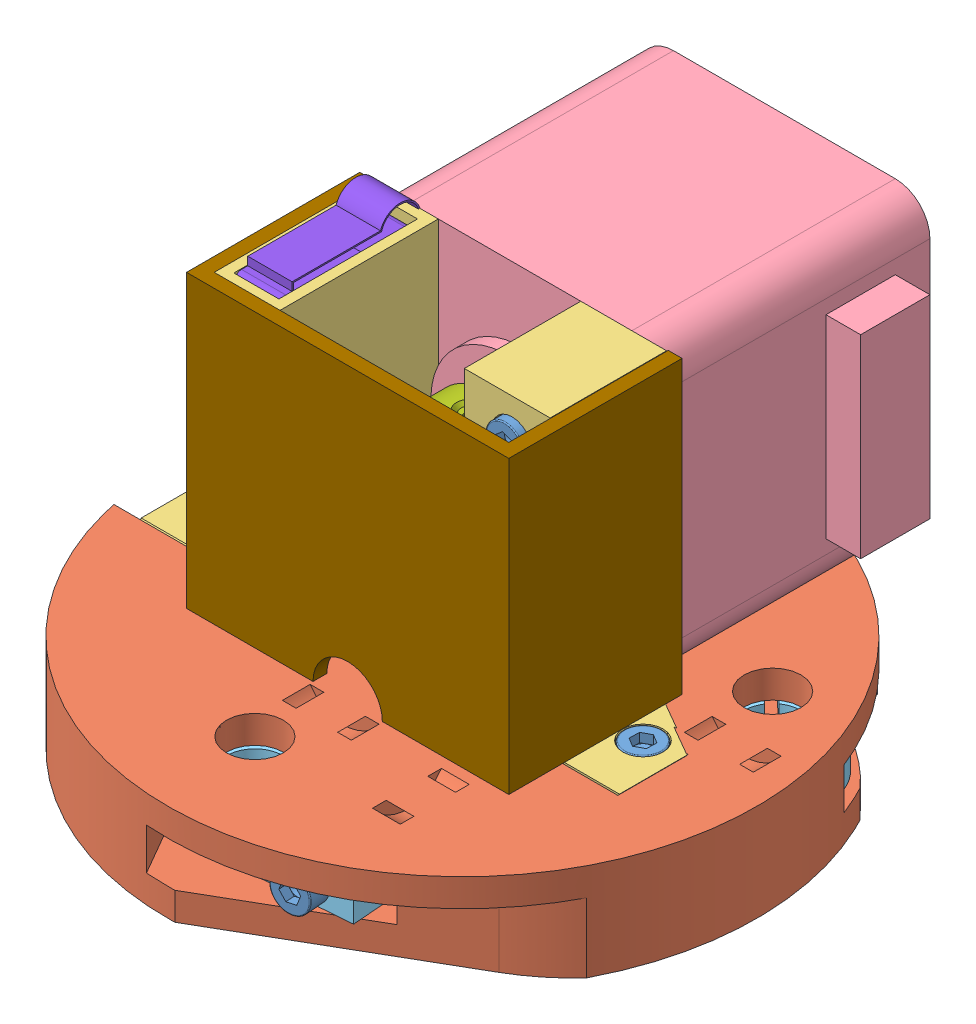
SolidWorks assembly PBaseAssembly, configuration Default. Lengths in mm.
Overall size (84.11 73.25 88.9).
22 component instances, 9 part files, 47 mates.
Components (placement in the parent):
- socket head cap screw_iso-3: socket head cap screw_iso [ISO 4762 M3 x 12 - 12N] at (26.05 4 0) x (0 -1 0) z (-0.999667 0 -0.02581) size (15 5.5 5.5)
- socket head cap screw_iso-7: socket head cap screw_iso [ISO 4762 M3 x 25 - 18N] at (-15.45 9.5 9.5) x (0 0 -1) z (0.981841 0.189707 0) size (28 5.5 5.5)
- socket head cap screw_iso-9: socket head cap screw_iso [ISO 4762 M3 x 16 - 16N] at (26.7408 -3.2 -33.0956) x (-0.692817 0 0.721114) z (-0.029148 0.999183 -0.028004) size (19 5.5 5.5)
- socket head cap screw_iso-10: socket head cap screw_iso [ISO 4762 M3 x 16 - 16N] at (-24.012 -3.2 -35.3724) x (0.554046 0 0.832486) z (-0.142507 -0.985239 0.094843) size (19 5.5 5.5)
- socket head cap screw_iso-13: socket head cap screw_iso [ISO 4762 M3 x 16 - 16N] at (12.3868 -3.2 37.2961) x (-0.079917 0 -0.996801) z (-0.160824 0.986899 0.012894) size (19 5.5 5.5)
- socket head cap screw_iso-11: socket head cap screw_iso [ISO 4762 M3 x 25 - 18N] at (15.55 40.5 9.5) x (0 0 -1) z (0.981841 0.189707 0) size (28 5.5 5.5)
- socket head cap screw_iso-12: socket head cap screw_iso [ISO 4762 M3 x 25 - 18N] at (15.55 9.5 8.5) x (0 0 -1) z (0.998806 -0.048858 0) size (28 5.5 5.5)
- socket head cap screw_iso-4: socket head cap screw_iso [ISO 4762 M3 x 12 - 12N] at (-25.95 4 0) x (0 -1 0) z (0.992841 0 -0.119448) size (15 5.5 5.5)
- PFestRound-1: PFestRound [Default] at origin size (84.11 28 85)
- PStepperHolder-1: PStepperHolder [Mit Kabelfuehrung] at (0.05 24.6603 -8.4) x (-1 0 0) z (0 0 -1) size (69 52 23)
- _Stepper_NEMA17-1: _Stepper_NEMA17 [Standard] at (0.05 25 -46.4) x (0 1 0) z (0 0 1) size (42 47 52)
- PRodFix-1: PRodFix [Default] at (29.25 -6 -15.5) x (-0.692817 0 0.721114) z (-0.721114 0 -0.692817) size (15.9 5.6 27.95)
- PRodFix-3: PRodFix [Default] at (-29.6 -0.4 -18.5) x (0.554046 0 0.832486) z (0.832486 0 -0.554046) size (15.9 5.6 27.95)
- PRodFix-6: PRodFix [Default] at (-2.4435 -6 27.5) x (-0.079917 0 -0.996801) z (0.996801 0 -0.079917) size (15.9 5.6 27.95)
- hex nut style 1 gradeab_iso-1: hex nut style 1 gradeab_iso [ISO - 4032 - M3 - D - N] at (10.8764 -3.2 18.4566) x (0 1 0) z (-0.079917 0 -0.996801) size (5.5 6.35 2.4)
- hex nut style 1 gradeab_iso-2: hex nut style 1 gradeab_iso [ISO - 4032 - M3 - D - N] at (13.6465 -3.2 -19.4666) x (0 -1 0) z (-0.692817 0 0.721114) size (5.5 6.35 2.4)
- hex nut style 1 gradeab_iso-3: hex nut style 1 gradeab_iso [ISO - 4032 - M3 - D - N] at (-13.5405 -3.2 -19.6384) x (0.720954 0.5 -0.479818) z (0.554046 0 0.832486) size (5.5 6.35 2.4)
- hex nut style 1 gradeab_iso-4: hex nut style 1 gradeab_iso [ISO - 4032 - M3 - D - N] at (-25.95 -10 0) x (0.866025 0 -0.5) z (0 -1 0) size (5.5 6.35 2.4)
- hex nut style 1 gradeab_iso-5: hex nut style 1 gradeab_iso [ISO - 4032 - M3 - D - N] at (26.05 -10 0) x (-0.866025 0 -0.5) z (0 -1 0) size (5.5 6.35 2.4)
- _Riemenscheibe_GT2_20T-1: _Riemenscheibe_GT2_20T [Конфигурация1] at (0.05 25 -3.8) x (0 0 1) z (-0.98079 0.195066 0) size (16 16 16)
- _Endschalter_15,6mm-2: _Endschalter_15,6mm [Default] at (-19.7782 35.8 3.2) x (0 0 -1) z (1 0 0) size (20.35 17.35 6.4)
- PStepperHolder_Cover-1: PStepperHolder_Cover [Default] at (-0.1282 25 14.4321) x (0 0 1) z (0 1 0) size (25 46.5 42)
Mates (geometry in assembly coordinates):
- Coincident1: coincident anti-aligned: plane of PFestRound-1 through (0 -6 0) normal (0 1 0); plane of PStepperHolder-1 through (-37.95 -6 -8.4) normal (0 -1 0)
- Concentric2: concentric aligned: cylinder of PFestRound-1 through (26.05 -10 0) axis (0 1 0) radius 1.7; cylinder of PStepperHolder-1 through (26.05 -6 0) axis (0 1 0) radius 1.7
- Concentric6: concentric aligned: cylinder of PStepperHolder-1 through (26.05 -6 0) axis (0 1 0) radius 1.7; cylinder of socket head cap screw_iso-3 through (26.05 35.75 0) axis (0 1 0) radius 1.5
- Coincident4: coincident anti-aligned: plane of PStepperHolder-1 through (26.05 1 0) normal (0 1 0); plane of socket head cap screw_iso-3 through (25.979 1 2.7491) normal (0 -1 0)
- Concentric9: concentric aligned: cylinder of PStepperHolder-1 through (-25.95 -6 0) axis (0 1 0) radius 1.7; cylinder of socket head cap screw_iso-4 through (-25.95 35.75 0) axis (0 1 0) radius 1.5
- Coincident7: coincident anti-aligned: plane of PStepperHolder-1 through (-25.95 1 0) normal (0 1 0); plane of socket head cap screw_iso-4 through (-26.2785 1 -2.7303) normal (0 -1 0)
- Concentric15: concentric aligned: cylinder of PFestRound-1 through (29.25 4 -15.5) axis (0 -1 0) radius 4.1; cylinder of PRodFix-1 through (29.25 -0.4 -15.5) axis (0 -1 0) radius 4.05
- Coincident13: coincident anti-aligned: plane of PFestRound-1 through (0 -6 0) normal (0 1 0); plane of PRodFix-1 through (29.25 -6 -15.5) normal (0 -1 0)
- Concentric17: concentric aligned: cylinder of PRodFix-1 through (13.6465 -3.2 -19.4666) axis (0.692817 0 -0.721114) radius 1.7; cylinder of socket head cap screw_iso-9 through (48.7377 -3.2 -55.991) axis (0.692817 0 -0.721114) radius 1.5
- Coincident14: coincident anti-aligned: plane of PRodFix-1 through (20.3356 -0.4 -35.0892) normal (0.692817 0 -0.721114); plane of socket head cap screw_iso-9 through (26.6437 -3.0888 -29.0286) normal (-0.692817 0 0.721114)
- Concentric18: concentric anti-aligned: cylinder of PFestRound-1 through (-29.6 4 -18.5) axis (0 -1 0) radius 4.1; cylinder of PRodFix-3 through (-29.6 -6 -18.5) axis (0 1 0) radius 4.05
- Coincident15: coincident anti-aligned: plane of PFestRound-1 through (0 -6 0) normal (0 1 0); plane of PRodFix-3 through (-29.6 -6 -18.5) normal (0 -1 0)
- Concentric19: concentric aligned: cylinder of PRodFix-3 through (-13.5405 -3.2 -19.6384) axis (-0.554046 0 -0.832486) radius 1.7; cylinder of socket head cap screw_iso-10 through (-41.603 -3.2 -61.8038) axis (-0.554046 0 -0.832486) radius 1.5
- Coincident16: coincident anti-aligned: plane of PRodFix-3 through (-17.3549 -6 -36.1992) normal (-0.554046 0 -0.832486); plane of socket head cap screw_iso-10 through (-24.6054 -2.7292 -31.3738) normal (0.554046 0 0.832486)
- Concentric21: concentric aligned: cylinder of socket head cap screw_iso-7 through (-15.45 9.5 41.25) axis (0 0 1) radius 1.5; cylinder of _Stepper_NEMA17-1 through (-15.45 9.5 -18.4) axis (0 0 1) radius 1.5
- Concentric22: concentric anti-aligned: cylinder of PStepperHolder-1 through (15.55 40.5 8.4) axis (0 0 -1) radius 1.7; cylinder of _Stepper_NEMA17-1 through (15.55 40.5 -18.4) axis (0 0 1) radius 1.5
- Coincident17: coincident anti-aligned: plane of PStepperHolder-1 through (0.05 24.6603 -8.4) normal (0 0 -1); plane of _Stepper_NEMA17-1 through (0.05 25 -8.4) normal (0 0 1)
- Concentric23: concentric anti-aligned: cylinder of PStepperHolder-1 through (-15.45 9.5 8.4) axis (0 0 -1) radius 1.7; cylinder of socket head cap screw_iso-7 through (-15.45 9.5 41.25) axis (0 0 1) radius 1.5
- Concentric24: concentric aligned: cylinder of _Stepper_NEMA17-1 through (15.55 40.5 -18.4) axis (0 0 1) radius 1.5; cylinder of socket head cap screw_iso-11 through (15.55 40.5 41.25) axis (0 0 1) radius 1.5
- Concentric25: concentric anti-aligned: cylinder of PStepperHolder-1 through (15.55 9.5 8.4) axis (0 0 -1) radius 1.7; cylinder of socket head cap screw_iso-12 through (15.55 9.5 40.25) axis (0 0 1) radius 1.5
- Concentric26: concentric aligned: cylinder of PFestRound-1 through (-2.4435 4 27.5) axis (0 -1 0) radius 4.1; cylinder of PRodFix-6 through (-2.4435 -0.4 27.5) axis (0 -1 0) radius 4.05
- Coincident21: coincident anti-aligned: plane of PFestRound-1 through (0 -6 0) normal (0 1 0); plane of PRodFix-6 through (-2.4435 -6 27.5) normal (0 -1 0)
- Concentric27: concentric aligned: cylinder of PRodFix-6 through (10.8764 -3.2 18.4566) axis (0.079917 0 0.996801) radius 1.7; cylinder of socket head cap screw_iso-13 through (14.9242 -3.2 68.9446) axis (0.079917 0 0.996801) radius 1.5
- Coincident22: coincident anti-aligned: plane of PRodFix-6 through (18.1279 -0.4 33.8262) normal (0.079917 0 0.996801); plane of socket head cap screw_iso-13 through (9.4418 -3.6437 34.5226) normal (-0.079917 0 -0.996801)
- Concentric28: concentric anti-aligned: cylinder of socket head cap screw_iso-13 through (14.9242 -3.2 68.9446) axis (0.079917 0 0.996801) radius 1.5; cylinder of hex nut style 1 gradeab_iso-1 through (11.0682 -3.2 20.8489) axis (-0.079917 0 -0.996801) radius 1.25
- Coincident23: coincident anti-aligned: plane of PRodFix-6 through (-2.887 -6 21.9678) normal (-0.079917 0 -0.996801); plane of hex nut style 1 gradeab_iso-1 through (14.2335 -3.2 20.5951) normal (0.079917 0 0.996801)
- Parallel1: parallel anti-aligned: plane of PRodFix-6 through (12.9098 -6 20.7013) normal (-0.863255 0.5 0.06921); plane of hex nut style 1 gradeab_iso-1 through (14.2335 -3.2 20.5951) normal (0.863255 -0.5 -0.06921)
- Concentric29: concentric anti-aligned: cylinder of socket head cap screw_iso-9 through (48.7377 -3.2 -55.991) axis (0.692817 0 -0.721114) radius 1.5; cylinder of hex nut style 1 gradeab_iso-2 through (15.3093 -3.2 -21.1973) axis (-0.692817 0 0.721114) radius 1.25
- Coincident25: coincident anti-aligned: plane of PRodFix-1 through (25.4049 -6 -11.4978) normal (-0.692817 0 0.721114); plane of hex nut style 1 gradeab_iso-2 through (17.5991 -3.2 -18.9973) normal (0.692817 0 -0.721114)
- Parallel2: parallel aligned: plane of PRodFix-1 through (17.8073 -3.2 -18.7973) normal (-0.624503 0.5 -0.599997); plane of hex nut style 1 gradeab_iso-2 through (14.1644 -0.45 -22.2973) normal (-0.624503 0.5 -0.599997)
- Coincident27: coincident anti-aligned: cylinder of socket head cap screw_iso-10 through (-41.603 -3.2 -61.8038) axis (-0.554046 0 -0.832486) radius 1.5; circle of hex nut style 1 gradeab_iso-3
- Coincident28: coincident anti-aligned: plane of PRodFix-3 through (-26.525 -0.4 -13.8797) normal (0.554046 0 0.832486); plane of hex nut style 1 gradeab_iso-3 through (-16.192 -0.45 -20.7567) normal (-0.554046 0 -0.832486)
- Parallel3: parallel aligned: plane of PRodFix-3 through (-16.4083 -6 -20.6127) normal (0.720954 0.5 -0.479818); plane of hex nut style 1 gradeab_iso-3 through (-13.5485 -0.45 -22.516) normal (0.720954 0.5 -0.479818)
- Concentric30: concentric aligned: cone of socket head cap screw_iso-4 through (-25.95 -11 0) axis (0 -1 0); cylinder of hex nut style 1 gradeab_iso-4 through (-25.95 15.0375 0) axis (0 -1 0) radius 1.5
- Concentric31: concentric aligned: cone of socket head cap screw_iso-3 through (26.05 -11 0) axis (0 -1 0); cylinder of hex nut style 1 gradeab_iso-5 through (26.05 15.0375 0) axis (0 -1 0) radius 1.5
- Parallel4: parallel: line of PFestRound-1 through (22.4704 -10 0) axis (0.5 0 -0.866025); plane of hex nut style 1 gradeab_iso-5 through (24.4623 -7.6 -2.75) normal (-0.866025 0 -0.5)
- Parallel5: parallel: line of PFestRound-1 through (-29.6296 -10 0) axis (0.5 0 -0.866025); plane of hex nut style 1 gradeab_iso-4 through (-29.1254 -7.6 0) normal (-0.866025 0 -0.5)
- Coincident34: coincident anti-aligned: plane of PFestRound-1 through (0 -7.6 0) normal (0 -1 0); plane of hex nut style 1 gradeab_iso-5 through (27.6377 -7.6 -2.75) normal (0 1 0)
- Coincident35: coincident anti-aligned: plane of PFestRound-1 through (0 -7.6 0) normal (0 -1 0); plane of hex nut style 1 gradeab_iso-4 through (-24.3623 -7.6 2.75) normal (0 1 0)
- Concentric32: concentric anti-aligned: cylinder of _Stepper_NEMA17-1 through (0.05 25 5.6) axis (0 0 -1) radius 2.5; circle of _Riemenscheibe_GT2_20T-1
- Coincident42: coincident anti-aligned: plane of PStepperHolder-1 through (-13.3782 35.8 13.1) normal (0 0 -1); plane of _Endschalter_15,6mm-2 through (-13.3782 35.8 13.1) normal (0 0 1)
- Coincident43: coincident anti-aligned: plane of PStepperHolder-1 through (-13.3782 35.8 13.1) normal (-1 0 0); plane of _Endschalter_15,6mm-2 through (-13.3782 46.25 -4.4) normal (1 0 0)
- Coincident44: coincident anti-aligned: plane of PStepperHolder-1 through (0.05 35.8 -8.4) normal (0 1 0); plane of _Endschalter_15,6mm-2 through (-13.3782 35.8 13.1) normal (0 -1 0)
- Parallel7: parallel anti-aligned: plane of PFestRound-1 through (21 4 -8.675) normal (0 0 1); plane of PStepperHolder-1 through (0.05 24.6603 -8.4) normal (0 0 -1)
- Coincident45: coincident: cone of _Stepper_NEMA17-1 through (0.05 25 -3) axis (0 0 1); circle of _Riemenscheibe_GT2_20T-1
- Coincident49: coincident anti-aligned: plane of PStepperHolder-1 through (-21.3782 35.8 14.6) normal (-1 0 0); plane of PStepperHolder_Cover-1 through (-21.3782 4 -8.5679) normal (1 0 0)
- Coincident50: coincident anti-aligned: plane of PFestRound-1 through (0 4 0) normal (0 1 0); plane of PStepperHolder_Cover-1 through (-23.3782 4 16.4321) normal (0 -1 0)
